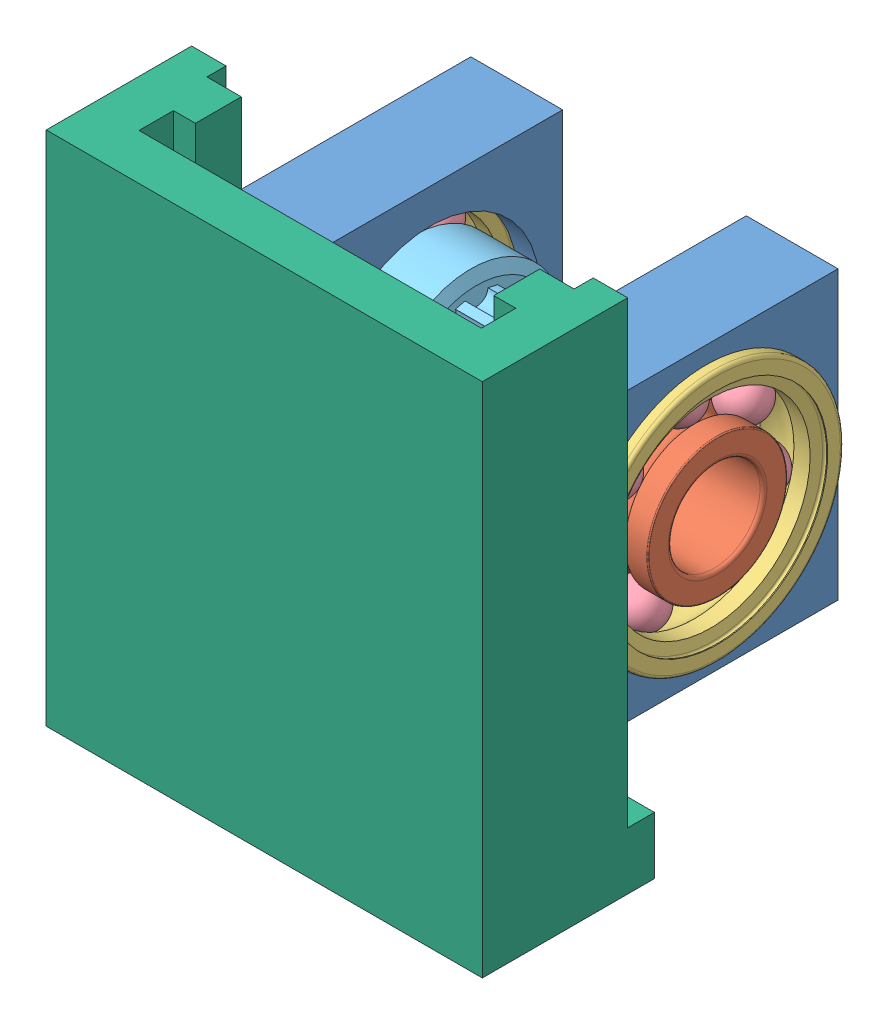
SolidWorks assembly return_pully, configuration Standard. Lengths in mm.
Overall size (38 45 34).
37 component instances, 7 part files, 8 mates.
Components (placement in the parent):
- return_pully_holder-1: return_pully_holder [Standard] at (-1.4973 -12.4501 43) size (32 25 30)
- 608-2Z-1: 608-2Z [Standard] at (-18.4973 0.0499 28.5) size (7 22 22)
  - 608-2Z_PART1-1: 608-2Z_PART1 [Standard] at origin size (7 19.2 19.2)
  - 608-2Z_PART2-1: 608-2Z_PART2 [Standard] at origin size (7 22 22)
  - 608-2Z_PART3-1: 608-2Z_PART3 [Standard] at origin size (3.97 3.97 3.97)
  - 608-2Z_PART3-2: 608-2Z_PART3 [Standard] x (1 0 0) z (0 0.781831 0.62349) size (3.97 3.97 3.97)
  - 608-2Z_PART3-3: 608-2Z_PART3 [Standard] x (1 0 0) z (0 0.974928 -0.222521) size (3.97 3.97 3.97)
  - 608-2Z_PART3-4: 608-2Z_PART3 [Standard] x (1 0 0) z (0 0.433884 -0.900969) size (3.97 3.97 3.97)
  - 608-2Z_PART3-5: 608-2Z_PART3 [Standard] x (1 0 0) z (0 -0.433884 -0.900969) size (3.97 3.97 3.97)
  - 608-2Z_PART3-6: 608-2Z_PART3 [Standard] x (1 0 0) z (0 -0.974928 -0.222521) size (3.97 3.97 3.97)
  - 608-2Z_PART3-7: 608-2Z_PART3 [Standard] x (1 0 0) z (0 -0.781831 0.62349) size (3.97 3.97 3.97)
  - 608-2Z_PART4-1: 608-2Z_PART4 [Standard] at origin
  - 608-2Z_PART4-2: 608-2Z_PART4 [Standard] x (1 0 0) z (0 0.781831 0.62349)
  - 608-2Z_PART4-3: 608-2Z_PART4 [Standard] x (1 0 0) z (0 0.974928 -0.222521)
  - 608-2Z_PART4-4: 608-2Z_PART4 [Standard] x (1 0 0) z (0 0.433884 -0.900969)
  - 608-2Z_PART4-5: 608-2Z_PART4 [Standard] x (1 0 0) z (0 -0.433884 -0.900969)
  - 608-2Z_PART4-6: 608-2Z_PART4 [Standard] x (1 0 0) z (0 -0.974928 -0.222521)
  - 608-2Z_PART4-7: 608-2Z_PART4 [Standard] x (1 0 0) z (0 -0.781831 0.62349)
- 608-2Z-2: 608-2Z [Standard] at (8.5027 0.0499 28.5) size (7 22 22)
  - 608-2Z_PART1-1: 608-2Z_PART1 [Standard] at origin size (7 19.2 19.2)
  - 608-2Z_PART2-1: 608-2Z_PART2 [Standard] at origin size (7 22 22)
  - 608-2Z_PART3-1: 608-2Z_PART3 [Standard] at origin size (3.97 3.97 3.97)
  - 608-2Z_PART3-2: 608-2Z_PART3 [Standard] x (1 0 0) z (0 0.781831 0.62349) size (3.97 3.97 3.97)
  - 608-2Z_PART3-3: 608-2Z_PART3 [Standard] x (1 0 0) z (0 0.974928 -0.222521) size (3.97 3.97 3.97)
  - 608-2Z_PART3-4: 608-2Z_PART3 [Standard] x (1 0 0) z (0 0.433884 -0.900969) size (3.97 3.97 3.97)
  - 608-2Z_PART3-5: 608-2Z_PART3 [Standard] x (1 0 0) z (0 -0.433884 -0.900969) size (3.97 3.97 3.97)
  - 608-2Z_PART3-6: 608-2Z_PART3 [Standard] x (1 0 0) z (0 -0.974928 -0.222521) size (3.97 3.97 3.97)
  - 608-2Z_PART3-7: 608-2Z_PART3 [Standard] x (1 0 0) z (0 -0.781831 0.62349) size (3.97 3.97 3.97)
  - 608-2Z_PART4-1: 608-2Z_PART4 [Standard] at origin
  - 608-2Z_PART4-2: 608-2Z_PART4 [Standard] x (1 0 0) z (0 0.781831 0.62349)
  - 608-2Z_PART4-3: 608-2Z_PART4 [Standard] x (1 0 0) z (0 0.974928 -0.222521)
  - 608-2Z_PART4-4: 608-2Z_PART4 [Standard] x (1 0 0) z (0 0.433884 -0.900969)
  - 608-2Z_PART4-5: 608-2Z_PART4 [Standard] x (1 0 0) z (0 -0.433884 -0.900969)
  - 608-2Z_PART4-6: 608-2Z_PART4 [Standard] x (1 0 0) z (0 -0.974928 -0.222521)
  - 608-2Z_PART4-7: 608-2Z_PART4 [Standard] x (1 0 0) z (0 -0.781831 0.62349)
- Pulley 1-1: Pulley 1 [Default] at (-11.4973 0.0499 28.5) size (14.8 16 16)
- return_pully_tightener-1: return_pully_tightener [Standard] at (-1.4973 -17.4694 41.9425) x (1 0 0) z (0 1 0) size (38 15 45)
Mates (geometry in assembly coordinates):
- Konzentrisch1: concentric anti-aligned: cylinder of return_pully_holder-1 through (8.5027 0.0499 28.5) axis (1 0 0) radius 11; cylinder of 608-2Z-2/608-2Z_PART2-1 through (58.5027 0.0499 28.5) axis (-1 0 0) radius 11
- Deckungsgleich1: coincident anti-aligned: plane of return_pully_holder-1 through (8.5027 0.0499 28.5) normal (1 0 0); plane of 608-2Z-2/608-2Z_PART2-1 through (8.5027 10.7499 28.5) normal (-1 0 0)
- Konzentrisch2: concentric aligned: cylinder of return_pully_holder-1 through (-11.4973 0.0499 28.5) axis (-1 0 0) radius 11; cylinder of 608-2Z-1/608-2Z_PART2-1 through (31.5027 0.0499 28.5) axis (-1 0 0) radius 11
- Deckungsgleich2: coincident anti-aligned: plane of return_pully_holder-1 through (-11.4973 0.0499 28.5) normal (-1 0 0); plane of 608-2Z-1/608-2Z_PART2-1 through (-11.4973 9.6499 28.5) normal (1 0 0)
- Konzentrisch3: concentric anti-aligned: cylinder of 608-2Z-1/608-2Z_PART1-1 through (31.5027 0.0499 28.5) axis (-1 0 0) radius 4; cylinder of Pulley 1-1 through (-11.4973 0.0499 28.5) axis (1 0 0) radius 2.5
- Deckungsgleich3: coincident anti-aligned: plane of 608-2Z-1/608-2Z_PART1-1 through (-11.4973 4.3499 28.5) normal (1 0 0); plane of Pulley 1-1 through (-11.4973 7.0499 28.5) normal (-1 0 0)
- Deckungsgleich4: coincident anti-aligned: plane of return_pully_holder-1 through (11.5027 12.5499 40) normal (1 0 0); plane of return_pully_tightener-1 through (11.5027 22.5306 40) normal (-1 0 0)
- Deckungsgleich5: coincident anti-aligned: plane of return_pully_holder-1 through (14.5027 12.5499 40) normal (0 0 1); plane of return_pully_tightener-1 through (14.5027 22.5306 40) normal (0 0 -1)
